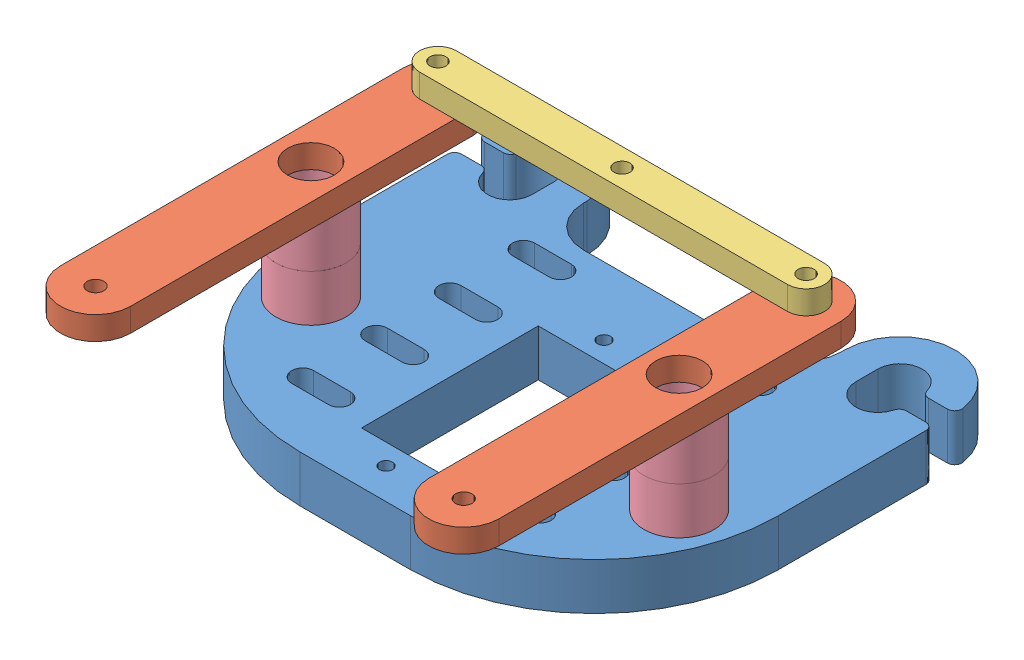
SolidWorks assembly Assem1, configuration Default. Lengths in mm.
Overall size (65 25.4 71.51).
8 component instances, 4 part files, 14 mates.
Components (placement in the parent):
- Base-1: Base [Default] at (11.5558 29.3091 68.2011) size (65 6.35 56.5)
- Bell Twist-1: Bell Twist [Default] at (4.729 48.3591 66.0799) size (9.53 3.17 56.03)
- ServoConnection-1: ServoConnection [Default] at (3.2816 51.5341 50.0608) size (55 3.17 5)
- Spacer_4-1: Spacer_4 [Default] at (-6.7402 35.6591 63.2866) size (9.53 6.35 9.53)
- Spacer_4-2: Spacer_4 [Default] at (43.2598 48.3591 63.2866) x (-0.837169 0 -0.546944) z (-0.546944 0 0.837169) size (9.53 6.35 9.53)
- Spacer_4-3: Spacer_4 [Default] at (-6.7402 48.3591 63.2866) x (-0.837169 0 -0.546944) z (-0.546944 0 0.837169) size (9.53 6.35 9.53)
- Spacer_4-4: Spacer_4 [Default] at (43.2598 42.0091 63.2866) x (-0.837169 0 -0.546944) z (-0.546944 0 0.837169) size (9.53 6.35 9.53)
- Bell Twist-2: Bell Twist [Default] at (54.729 48.3591 66.0799) size (9.53 3.17 56.03)
Mates (geometry in assembly coordinates):
- Coincident1: coincident anti-aligned: plane of Base-1 through (-6.7402 35.6591 33.2866) normal (0 1 0); plane of Spacer_4-1 through (-35.4133 35.6591 66.0459) normal (0 -1 0)
- Coincident2: coincident anti-aligned: plane of Spacer_4-1 through (-35.4133 42.0091 66.0459) normal (0 1 0); plane of Spacer_4-3 through (-35.4133 42.0091 66.0459) normal (0 -1 0)
- Coincident3: coincident anti-aligned: plane of Base-1 through (-6.7402 35.6591 33.2866) normal (0 1 0); plane of Spacer_4-4 through (43.2598 35.6591 63.2866) normal (0 -1 0)
- Coincident4: coincident anti-aligned: plane of Spacer_4-2 through (43.2598 42.0091 63.2866) normal (0 -1 0); plane of Spacer_4-4 through (43.2598 42.0091 63.2866) normal (0 1 0)
- Concentric4: concentric aligned: cylinder of Spacer_4-2 through (43.2598 42.0091 63.2866) axis (0 1 0) radius 3.175; cylinder of Spacer_4-4 through (43.2598 35.6591 63.2866) axis (0 1 0) radius 3.175
- Concentric5: concentric anti-aligned: cylinder of Spacer_4-1 through (-6.7402 42.0091 63.2866) axis (0 -1 0) radius 3.175; cylinder of Spacer_4-3 through (-6.7402 42.0091 63.2866) axis (0 1 0) radius 3.175
- Concentric6: concentric aligned: cylinder of Base-1 through (-6.7402 35.6591 63.2866) axis (0 -1 0) radius 1.8529; cylinder of Spacer_4-1 through (-6.7402 42.0091 63.2866) axis (0 -1 0) radius 3.175
- Concentric7: concentric anti-aligned: cylinder of Base-1 through (43.2598 35.6591 63.2866) axis (0 -1 0) radius 1.8529; cylinder of Spacer_4-4 through (43.2598 35.6591 63.2866) axis (0 1 0) radius 3.175
- Coincident5: coincident: plane of Spacer_4-2 through (43.2598 48.3591 63.2866) normal (0 1 0); plane of Bell Twist-2 through (43.2598 48.3591 46.0366) normal (0 -1 0)
- Concentric8: concentric anti-aligned: cylinder of Spacer_4-2 through (43.2598 42.0091 63.2866) axis (0 1 0) radius 3.175; cylinder of Bell Twist-2 through (43.2598 51.5341 63.2866) axis (0 -1 0) radius 3.175
- Coincident6: coincident: plane of Bell Twist-1 through (-6.7402 48.3591 46.0366) normal (0 -1 0); plane of Spacer_4-3 through (-6.7402 48.3591 63.2866) normal (0 1 0)
- Concentric9: concentric anti-aligned: cylinder of Bell Twist-1 through (-6.7402 51.5341 63.2866) axis (0 -1 0) radius 3.175; cylinder of Spacer_4-3 through (-6.7402 42.0091 63.2866) axis (0 1 0) radius 3.175
- Concentric10: concentric: cylinder of Bell Twist-1 through (-6.7402 51.5341 46.0366) axis (0 -1 0) radius 1.0922; cylinder of ServoConnection-1 through (-6.7402 54.7091 46.0366) axis (0 -1 0) radius 1.0922
- Coincident7: coincident anti-aligned: plane of Bell Twist-1 through (-6.7402 51.5341 46.0366) normal (0 1 0); plane of ServoConnection-1 through (-6.7402 51.5341 46.0366) normal (0 -1 0)
